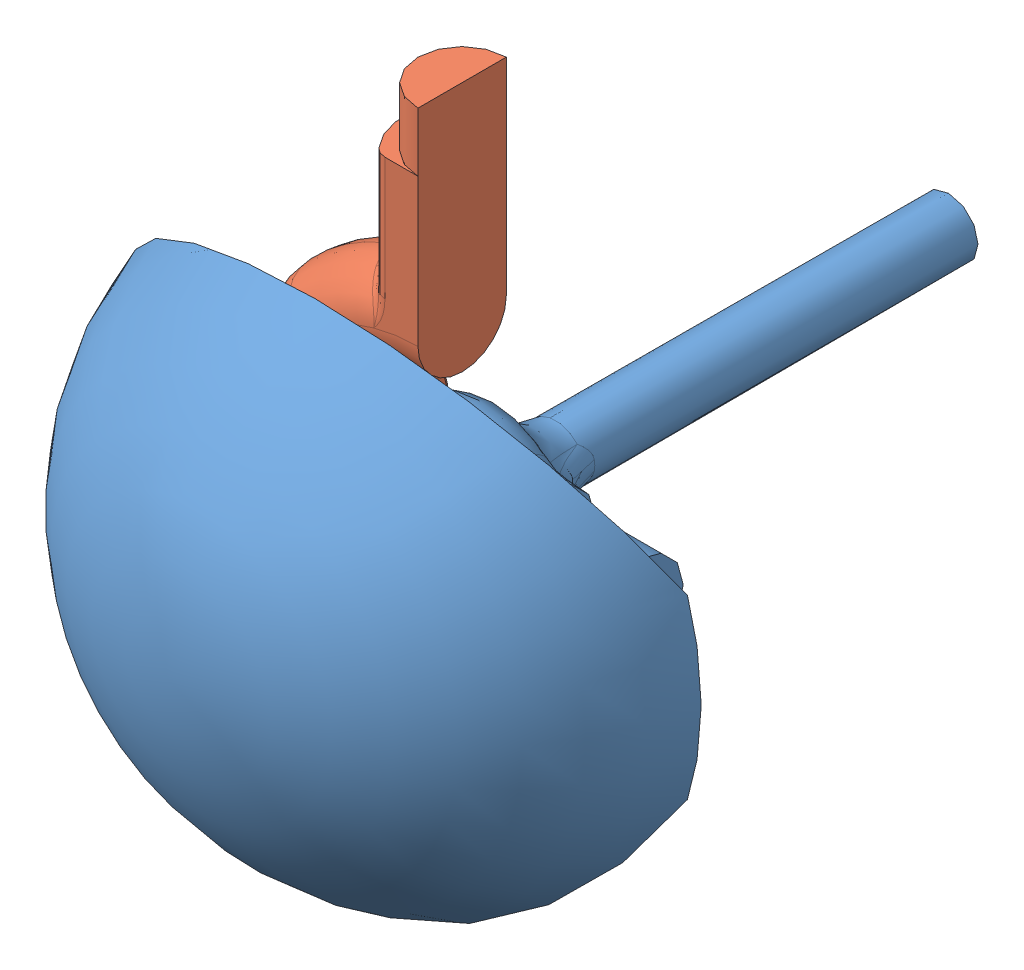
SolidWorks assembly gim, configuration Default. Lengths in mm.
Overall size (19.7 20.31 26.5).
2 component instances, 2 part files, 4 mates.
Components (placement in the parent):
- gimbal_test-1: gimbal_test [Default] at (-29.1631 6.4934 10.9774) size (19.7 17.32 26.5)
- Part4-1: Part4 [Default] at (-29.1631 6.4934 12.4774) size (6.2 12.5 6)
Mates (geometry in assembly coordinates):
- InPlace2: in place: plane of gimbal_test-1 through (-29.1631 6.4934 12.4774) normal (0 0 1); plane of ? through (0 0 12.4774) normal (0 0 1); moOrthogonalPlaneRef_w of gimbal_test-1 through (-29.1631 6.4934 12.4774) normal (0 0 1); plane of ? through (0 0 12.4774) normal (0 1 0); plane of gimbal_test-1 through (-29.1631 6.4934 12.4774) normal (0 0 1); plane of ? through (0 0 12.4774) normal (1 0 0); plane of gimbal_test-1 through (-29.1631 6.4934 12.4774) normal (0 0 1); unknown of Part4-1
- Coincident4: coincident aligned: plane of gimbal_test-1; plane of Part4-1
- Coincident5: coincident aligned: moOrthogonalPlaneRef_w of gimbal_test-1 through (-29.1631 6.4934 12.4774) normal (0 1 0); plane of Part4-1 through (-29.1631 6.4934 12.4774) normal (0 1 0)
- Coincident6: coincident anti-aligned: moOrthogonalPlaneRef_w of gimbal_test-1 through (-29.1631 6.4934 12.4774) normal (-1 0 0); plane of Part4-1 through (-29.1631 6.4934 12.4774) normal (1 0 0)
